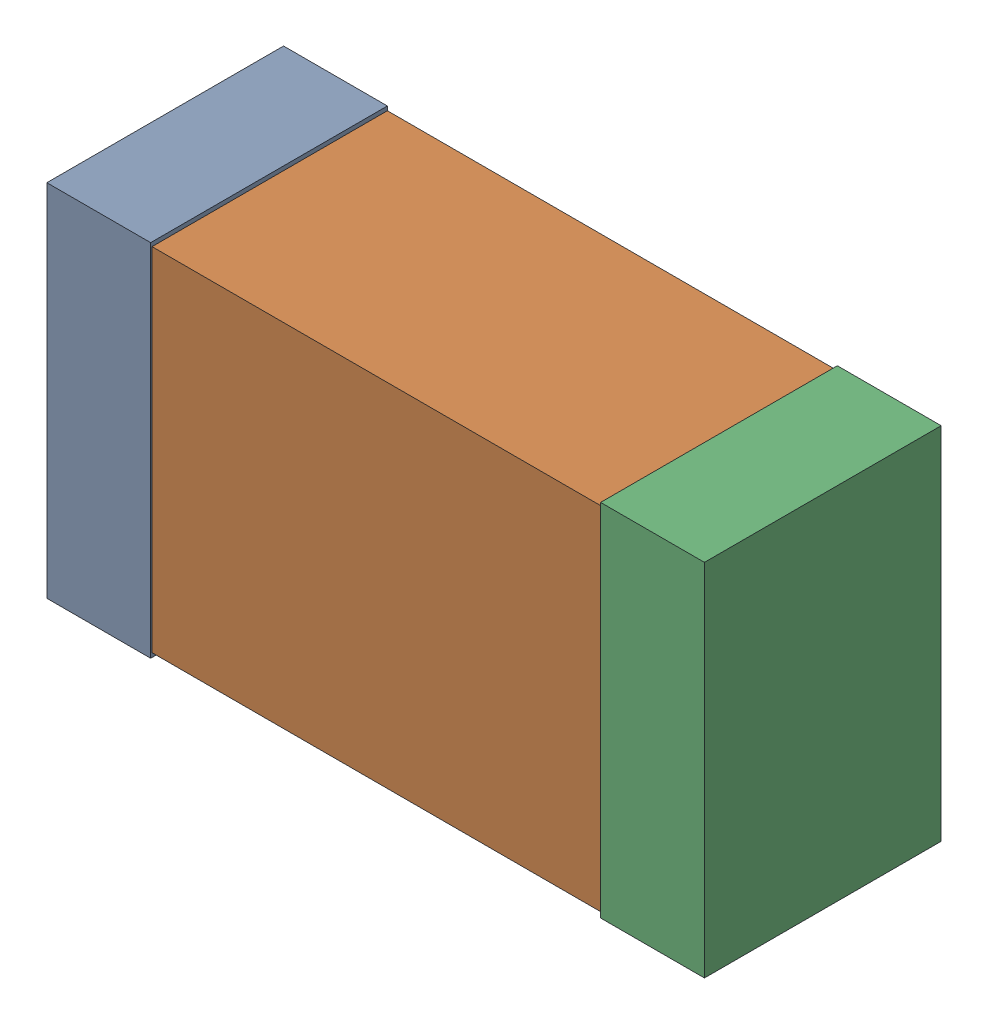
SolidWorks assembly R3_Motor_10Kanaloa_v2.0.0_Motor, configuration Default. Lengths in mm.
Overall size (2.38 1.3 0.85).
6 component instances, 2 part files, 0 mates.
Components (placement in the parent):
- 352877648-1: 352877648 [Default] at (84.344 175.768 0) size (0.38 1.3 0.85)
  - Extruded_14-1: Extruded_14 [Default] at origin size (0.38 1.3 0.85)
- 352877392-1: 352877392 [Default] at (85.344 175.768 0) size (2.2 1.27 0.85)
  - Extruded_15-1: Extruded_15 [Default] at origin size (2.2 1.27 0.85)
- 352877648-2: 352877648 [Default] at (86.344 175.768 0) size (0.38 1.3 0.85)
  - Extruded_14-1: Extruded_14 [Default] at origin size (0.38 1.3 0.85)
